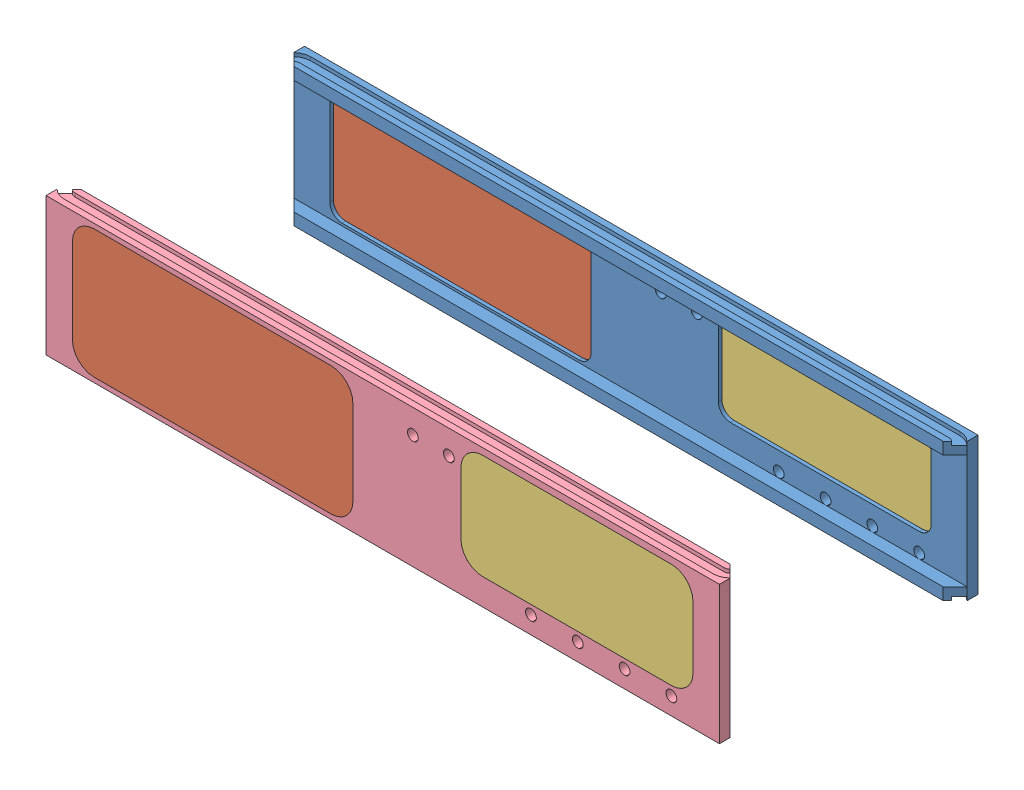
SolidWorks assembly side_plate_assembly, configuration Default. Lengths in mm.
Overall size (581 115 215.4).
6 component instances, 4 part files, 9 mates.
Components (placement in the parent):
- side_plate-1: side_plate [Default] at (14.3638 -73.645 -98.7) x (-1 0 0) z (0 0 -1) size (581 115 19)
- side_window_large-2: side_window_large [Default] at (14.3638 -116.145 -107.7) size (223.51 107 6)
- side_window_small-1: side_window_small [Default] at (14.3638 -73.645 -101.7) x (-1 0 0) z (0 0 -1) size (223.51 87.48 6)
- Mirrorside_plate-2: Mirrorside_plate [Default] at (14.3638 -73.645 98.7) x (-1 0 0) z (0 0 -1) size (581 115 19)
- side_window_large-3: side_window_large [Default] at (14.3638 -116.145 101.7) size (223.51 107 6)
- side_window_small-2: side_window_small [Default] at (14.3638 -73.645 107.7) x (-1 0 0) z (0 0 -1) size (223.51 87.48 6)
Mates (geometry in assembly coordinates):
- Concentric1: concentric aligned: cylinder of side_plate-1 through (-48.628 -109.145 -101.7) axis (0 0 -1) radius 18; cylinder of side_window_large-2 through (-48.628 -109.145 -101.7) axis (0 0 -1) radius 18
- Coincident1: coincident anti-aligned: plane of side_plate-1 through (-48.628 -109.145 -101.7) normal (0 0 -1); plane of side_window_large-2 through (-236.1362 -38.145 -101.7) normal (0 0 1)
- InPlace1: in place: plane of side_plate-1 through (234.7138 -93.145 -101.7) normal (0 0 -1); plane of ? through (0 0 -101.7) normal (0 0 -1); moOrthogonalPlaneRef_w of side_plate-1 through (234.7138 -93.145 -101.7) normal (0 0 -1); plane of ? through (0 0 -101.7) normal (0 1 0); plane of side_plate-1 through (234.7138 -93.145 -101.7) normal (0 0 -1); plane of ? through (0 0 -101.7) normal (-1 0 0); plane of side_plate-1 through (264.8638 -91.145 -101.7) normal (0 0 -1); unknown of side_window_small-1
- Coincident2: coincident aligned: plane of side_plate-1; plane of side_window_small-1
- Coincident3: coincident aligned: moOrthogonalPlaneRef_w of side_plate-1 through (14.3638 -73.645 -101.7) normal (0 1 0); plane of side_window_small-1 through (14.3638 -73.645 -101.7) normal (0 1 0)
- Coincident4: coincident anti-aligned: moOrthogonalPlaneRef_w of side_plate-1 through (14.3638 -73.645 -101.7) normal (1 0 0); plane of side_window_small-1 through (14.3638 -73.645 -101.7) normal (-1 0 0)
- Coincident2: coincident aligned: plane of side_plate-1 through (304.8638 -16.145 -107.7) normal (0 1 0); plane of Mirrorside_plate-2 through (304.8638 -16.145 107.7) normal (0 1 0)
- Parallel1: parallel anti-aligned: plane of side_plate-1 through (14.3638 -73.645 -98.7) normal (0 0 1); plane of Mirrorside_plate-2 through (14.3638 -73.645 98.7) normal (0 0 -1)
- Coincident4: coincident aligned: plane of side_plate-1 through (-276.1362 -16.145 -107.7) normal (-1 0 0); plane of Mirrorside_plate-2 through (-276.1362 -16.145 107.7) normal (-1 0 0)
